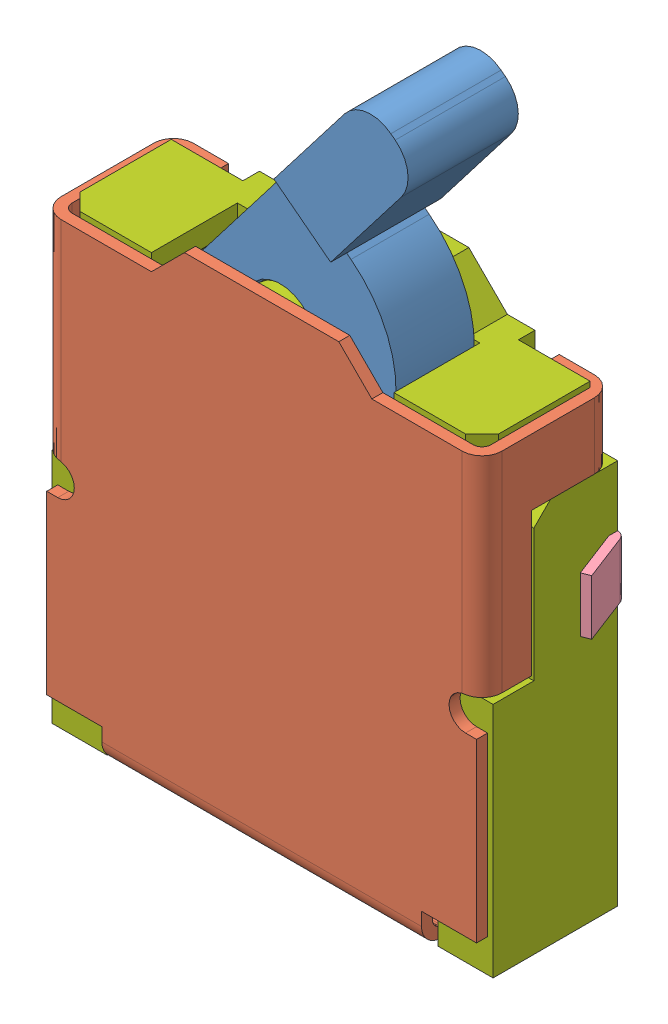
SolidWorks assembly ESE18R11B limit switch, configuration Default. Lengths in mm.
Overall size (4.53 6.66 1.63).
7 component instances, 7 part files, 0 mates.
Components (placement in the parent):
- sw-131-e18lv3-sk-1-1: sw-131-e18lv3-sk-1 [Default] at (0 1.7032 0.705) x (0.610145 0.79229 0) z (0 0 1) size (3.45 1.75 1)
- sw-131-e18fm4-sk-1-1: sw-131-e18fm4-sk-1 [Default] at (0 4.5758 1.23) size (4 4.4 1.2)
- sw-131-e18ts-j-sk-1-1: sw-131-e18ts-j-sk-1 [Default] at (0 0.0532 0) size (0.44 0.5 0.5)
- sw-131-e18ts-j-sk-1_2-1: sw-131-e18ts-j-sk-1_2 [Default] at (0 0.0532 0) size (0.44 0.5 0.5)
- sw-131-e18ts-j-sk-1_3-1: sw-131-e18ts-j-sk-1_3 [Default] at (0 0.0532 0) size (0.5 0.44 0.5)
- sw-131-e18ts-j-sk-1_4-1: sw-131-e18ts-j-sk-1_4 [Default] at (0 0.0532 0) size (0.5 0.44 0.5)
- sw-131-e18cs-boss-pc-1-1: sw-131-e18cs-boss-pc-1 [Default] at origin size (4 4.5 1.53)
